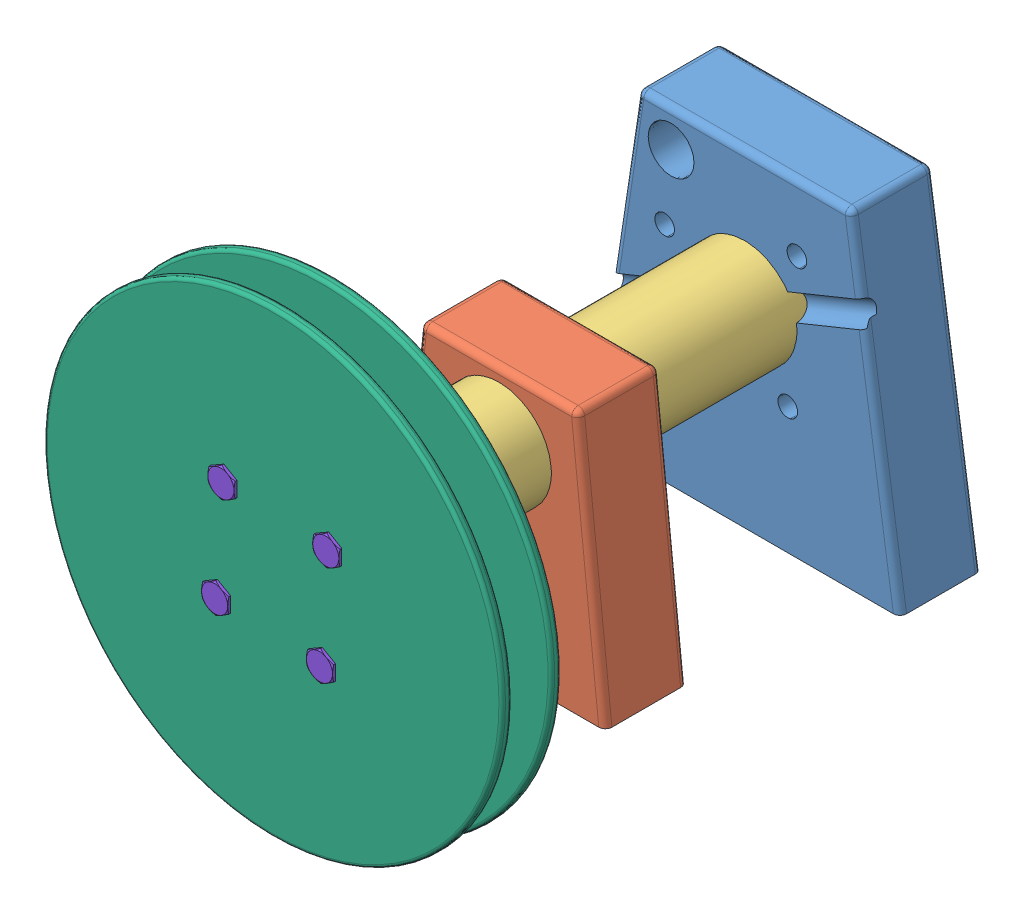
SolidWorks assembly winch-assembly, configuration Défaut. Lengths in mm.
Overall size (142.39 142.39 169.88).
17 component instances, 9 part files, 41 mates.
Components (placement in the parent):
- Winch-base-support-1: Winch-base-support [Défaut] at origin size (95 100 25.21)
- Winch-second-support-1: Winch-second-support [Défaut] at (1.4316 -43.5203 75) size (65 80 25)
- shaft-1: shaft [Défaut] at (11.9421 -27.1515 0) x (0.998141 -0.060949 0) z (0 0 1) size (32 32 151)
- drum-support-1: drum-support [Défaut] at (11.9421 -27.1515 133) x (-0.998141 0.060949 0) z (0.060949 0.998141 0) size (58 18 58)
- hex bolt gradec_iso-bis-1: hex bolt gradec_iso-bis [ISO 4016 - M6 x 35 x 18-WN] at (13.9763 6.1614 142) x (-0.060949 -0.998141 0) z (0.202033 -0.012337 -0.979301) size (39.38 11.55 10)
- hex bolt gradec_iso-bis-2: hex bolt gradec_iso-bis [ISO 4016 - M6 x 35 x 18-WN] at (9.9079 -60.4645 142) x (0.060949 0.998141 0) z (0.113515 -0.006932 0.993512) size (39.38 11.55 10)
- drum-external-plate-3: drum-external-plate [Défaut] at (11.9421 -27.1515 151) x (0.017229 0.999852 0) z (0 0 1) size (140 140 3)
- drum-internal-2: drum-internal [Défaut] at (11.9421 -27.1515 154) x (0.017229 0.999852 0) z (0 0 1) size (82 82 12)
- drum-external-plate-4: drum-external-plate [Défaut] at (11.9421 -27.1515 166) x (-0.017229 -0.999852 0) z (0 0 1) size (140 140 3)
- hex bolt gradec_iso-bis-3-1: hex bolt gradec_iso-bis-3 [ISO 4016 - M5 x 40 x 16-WN] at (26.9929 -43.8765 169.875) x (0 0 -1) z (1 0 0) size (43.88 9.24 8)
- hex bolt gradec_iso-bis-3-2: hex bolt gradec_iso-bis-3 [ISO 4016 - M5 x 40 x 16-WN] at (-5.0318 -41.921 169.875) x (0 0 -1) z (1 0 0) size (43.88 9.24 8)
- hex bolt gradec_iso-bis-3-3: hex bolt gradec_iso-bis-3 [ISO 4016 - M5 x 40 x 16-WN] at (-3.1087 -10.4265 169.875) x (0 0 -1) z (1 0 0) size (43.88 9.24 8)
- hex bolt gradec_iso-bis-3-4: hex bolt gradec_iso-bis-3 [ISO 4016 - M5 x 40 x 16-WN] at (28.916 -12.382 169.875) x (0 0 -1) z (1 0 0) size (43.88 9.24 8)
- hex nut gradec_iso-bis-2-1: hex nut gradec_iso-bis-2 [Hexagon Nut ISO - 4034 - M5 - N] at (-3.1087 -10.4265 127.4) x (-0.961271 -0.275604 0) z (0 0 -1) size (8 9.24 5.6)
- hex nut gradec_iso-bis-2-2: hex nut gradec_iso-bis-2 [Hexagon Nut ISO - 4034 - M5 - N] at (-5.0318 -41.921 127.4) x (0.923728 0.383049 0) z (0 0 -1) size (8 9.24 5.6)
- hex nut gradec_iso-bis-2-3: hex nut gradec_iso-bis-2 [Hexagon Nut ISO - 4034 - M5 - N] at (28.916 -12.382 133) size (8 9.24 5.6)
- hex nut gradec_iso-bis-2-4: hex nut gradec_iso-bis-2 [Hexagon Nut ISO - 4034 - M5 - N] at (26.9929 -43.8765 133) size (8 9.24 5.6)
Mates (geometry in assembly coordinates):
- Parallèle1: parallel aligned: plane of Winch-base-support-1 through (-35.5579 -87.1515 25) normal (0 -1 0); plane of Winch-second-support-1 through (-20.5579 -87.1515 100) normal (0 -1 0)
- Coaxiale1: concentric aligned: cylinder of Winch-base-support-1 through (11.9421 -27.1515 25) axis (0 0 -1) radius 16; cylinder of Winch-second-support-1 through (11.9421 -27.1515 100) axis (0 0 -1) radius 16
- Distance1: distance = 50 mm: line of Winch-second-support-1 through (-18.5466 -87.1515 75) axis (1 0 0); line of Winch-base-support-1 through (-33.5355 -87.1515 25) axis (1 0 0)
- Coaxiale2: concentric aligned: cylinder of Winch-second-support-1 through (11.9421 -27.1515 100) axis (0 0 -1) radius 16; cylinder of shaft-1 through (11.9421 -27.1515 151) axis (0 0 -1) radius 14.5
- Coïncidente3: coincident aligned: plane of Winch-base-support-1 through (-35.5579 -87.1515 0) normal (0 0 -1); plane of shaft-1 through (11.9421 -27.1515 0) normal (0 0 -1)
- Coaxiale6: concentric aligned: cylinder of shaft-1 through (11.9421 -27.1515 151) axis (0 0 -1) radius 16; cylinder of drum-support-1 through (11.9421 -27.1515 151) axis (0 0 -1) radius 16
- Coïncidente4: coincident aligned: plane of shaft-1 through (11.9421 -27.1515 151) normal (0 0 1); plane of drum-support-1 through (11.9421 -27.1515 151) normal (0 0 1)
- Coaxiale7: concentric aligned: cylinder of shaft-1 through (10.9669 -43.1218 142) axis (0.060949 0.998141 0) radius 3; cylinder of drum-support-1 through (10.1746 -56.0976 142) axis (0.060949 0.998141 0) radius 3
- Coaxiale8: concentric aligned: cylinder of drum-support-1 through (10.1746 -56.0976 142) axis (0.060949 0.998141 0) radius 3; cylinder of hex bolt gradec_iso-bis-1 through (13.9763 6.1614 142) axis (0.060949 0.998141 0) radius 3
- Tangent1: tangent anti-aligned: cylinder of drum-support-1 through (11.9421 -27.1515 151) axis (0 0 -1) radius 29; plane of hex bolt gradec_iso-bis-1 through (8.0661 2.1392 140.8314) normal (-0.060949 -0.998141 0)
- Coaxiale9: concentric anti-aligned: cylinder of drum-support-1 through (10.1746 -56.0976 142) axis (0.060949 0.998141 0) radius 3; cylinder of hex bolt gradec_iso-bis-2 through (9.9079 -60.4645 142) axis (-0.060949 -0.998141 0) radius 3
- Tangent2: tangent anti-aligned: cylinder of drum-support-1 through (11.9421 -27.1515 151) axis (0 0 -1) radius 29; plane of hex bolt gradec_iso-bis-2 through (4.4492 -55.748 142.6566) normal (0.060949 0.998141 0)
- Coïncidente5: coincident anti-aligned: plane of drum-support-1 through (11.9421 -27.1515 151) normal (0 0 1); plane of drum-external-plate-3 through (11.9421 -27.1515 151) normal (0 0 -1)
- Coaxiale11: concentric aligned: cylinder of drum-support-1 through (28.916 -12.382 151) axis (0 0 -1) radius 3; cylinder of drum-external-plate-3 through (28.916 -12.382 154) axis (0 0 -1) radius 3
- Coaxiale12: concentric aligned: cylinder of drum-support-1 through (26.9929 -43.8765 151) axis (0 0 -1) radius 3; cylinder of drum-external-plate-3 through (26.9929 -43.8765 154) axis (0 0 -1) radius 3
- Coaxiale13: concentric aligned: cylinder of drum-support-1 through (-5.0318 -41.921 151) axis (0 0 -1) radius 3; cylinder of drum-external-plate-3 through (-5.0318 -41.921 154) axis (0 0 -1) radius 3
- Coaxiale14: concentric aligned: cylinder of drum-support-1 through (-3.1087 -10.4265 151) axis (0 0 -1) radius 3; cylinder of drum-external-plate-3 through (-3.1087 -10.4265 154) axis (0 0 -1) radius 3
- Coïncidente6: coincident anti-aligned: plane of drum-external-plate-3 through (11.9421 -27.1515 154) normal (0 0 1); plane of drum-internal-2 through (11.9421 -27.1515 154) normal (0 0 -1)
- Coaxiale18: concentric aligned: cylinder of drum-support-1 through (28.916 -12.382 151) axis (0 0 -1) radius 3; cylinder of drum-internal-2 through (28.916 -12.382 166) axis (0 0 -1) radius 3
- Coaxiale19: concentric aligned: cylinder of drum-support-1 through (26.9929 -43.8765 151) axis (0 0 -1) radius 3; cylinder of drum-internal-2 through (26.9929 -43.8765 166) axis (0 0 -1) radius 3
- Coaxiale20: concentric aligned: cylinder of drum-support-1 through (-5.0318 -41.921 151) axis (0 0 -1) radius 3; cylinder of drum-internal-2 through (-5.0318 -41.921 166) axis (0 0 -1) radius 3.1258
- Coaxiale21: concentric aligned: cylinder of drum-support-1 through (-3.1087 -10.4265 151) axis (0 0 -1) radius 3; cylinder of drum-internal-2 through (-3.1087 -10.4265 166) axis (0 0 -1) radius 3
- Coïncidente7: coincident anti-aligned: plane of drum-internal-2 through (11.9421 -27.1515 166) normal (0 0 1); plane of drum-external-plate-4 through (11.9421 -27.1515 166) normal (0 0 -1)
- Coaxiale22: concentric aligned: cylinder of drum-internal-2 through (-5.0318 -41.921 166) axis (0 0 -1) radius 3.1258; cylinder of drum-external-plate-4 through (-5.0318 -41.921 169) axis (0 0 -1) radius 3
- Coaxiale23: concentric aligned: cylinder of drum-internal-2 through (26.9929 -43.8765 166) axis (0 0 -1) radius 3; cylinder of drum-external-plate-4 through (26.9929 -43.8765 169) axis (0 0 -1) radius 3
- Coaxiale24: concentric anti-aligned: cylinder of drum-internal-2 through (26.9929 -43.8765 166) axis (0 0 -1) radius 3; cylinder of hex bolt gradec_iso-bis-3-1 through (26.9929 -43.8765 169.875) axis (0 0 1) radius 2.5
- Coïncidente8: coincident anti-aligned: plane of drum-internal-2 through (11.9421 -27.1515 166) normal (0 0 1); plane of hex bolt gradec_iso-bis-3-1 through (26.9929 -39.2577 166) normal (0 0 -1)
- Coaxiale25: concentric anti-aligned: cylinder of drum-internal-2 through (-5.0318 -41.921 166) axis (0 0 -1) radius 3.1258; cylinder of hex bolt gradec_iso-bis-3-2 through (-5.0318 -41.921 169.875) axis (0 0 1) radius 2.5
- Coïncidente9: coincident anti-aligned: plane of drum-internal-2 through (11.9421 -27.1515 166) normal (0 0 1); plane of hex bolt gradec_iso-bis-3-2 through (-5.0318 -37.3022 166) normal (0 0 -1)
- Coaxiale26: concentric anti-aligned: cylinder of drum-internal-2 through (-3.1087 -10.4265 166) axis (0 0 -1) radius 3; cylinder of hex bolt gradec_iso-bis-3-3 through (-3.1087 -10.4265 169.875) axis (0 0 1) radius 2.5
- Coïncidente10: coincident anti-aligned: plane of drum-internal-2 through (11.9421 -27.1515 166) normal (0 0 1); plane of hex bolt gradec_iso-bis-3-3 through (-3.1087 -5.8077 166) normal (0 0 -1)
- Coaxiale27: concentric anti-aligned: cylinder of drum-internal-2 through (28.916 -12.382 166) axis (0 0 -1) radius 3; cylinder of hex bolt gradec_iso-bis-3-4 through (28.916 -12.382 169.875) axis (0 0 1) radius 2.5
- Coïncidente11: coincident anti-aligned: plane of drum-internal-2 through (11.9421 -27.1515 166) normal (0 0 1); plane of hex bolt gradec_iso-bis-3-4 through (28.916 -7.7632 166) normal (0 0 -1)
- Coaxiale28: concentric aligned: cone of hex bolt gradec_iso-bis-3-3 through (-3.1087 -10.4265 126) axis (0 0 -1); cylinder of hex nut gradec_iso-bis-2-1 through (-3.1087 -10.4265 152.4375) axis (0 0 -1) radius 2.5
- Coaxiale29: concentric anti-aligned: cylinder of hex bolt gradec_iso-bis-3-2 through (-5.0318 -41.921 169.875) axis (0 0 1) radius 2.5; cylinder of hex nut gradec_iso-bis-2-2 through (-5.0318 -41.921 152.4375) axis (0 0 -1) radius 2.5
- Coïncidente13: coincident anti-aligned: plane of drum-support-1 through (11.9421 -27.1515 133) normal (0 0 -1); plane of hex nut gradec_iso-bis-2-2 through (-3.2626 -46.1875 133) normal (0 0 1)
- Coaxiale30: concentric aligned: cylinder of hex bolt gradec_iso-bis-3-1 through (26.9929 -43.8765 169.875) axis (0 0 1) radius 2.5; cylinder of hex nut gradec_iso-bis-2-4 through (26.9929 -43.8765 127.4) axis (0 0 1) radius 2.1
- Coïncidente14: coincident anti-aligned: plane of drum-support-1 through (11.9421 -27.1515 133) normal (0 0 -1); plane of hex nut gradec_iso-bis-2-4 through (26.9929 -39.2577 133) normal (0 0 1)
- Coaxiale31: concentric aligned: cylinder of hex bolt gradec_iso-bis-3-4 through (28.916 -12.382 169.875) axis (0 0 1) radius 2.5; cylinder of hex nut gradec_iso-bis-2-3 through (28.916 -12.382 127.4) axis (0 0 1) radius 2.1
- Coïncidente15: coincident anti-aligned: plane of drum-support-1 through (11.9421 -27.1515 133) normal (0 0 -1); plane of hex nut gradec_iso-bis-2-3 through (28.916 -7.7632 133) normal (0 0 1)
- Coïncidente16: coincident anti-aligned: plane of drum-support-1 through (11.9421 -27.1515 133) normal (0 0 -1); plane of hex nut gradec_iso-bis-2-1 through (-4.3816 -5.9866 133) normal (0 0 1)
